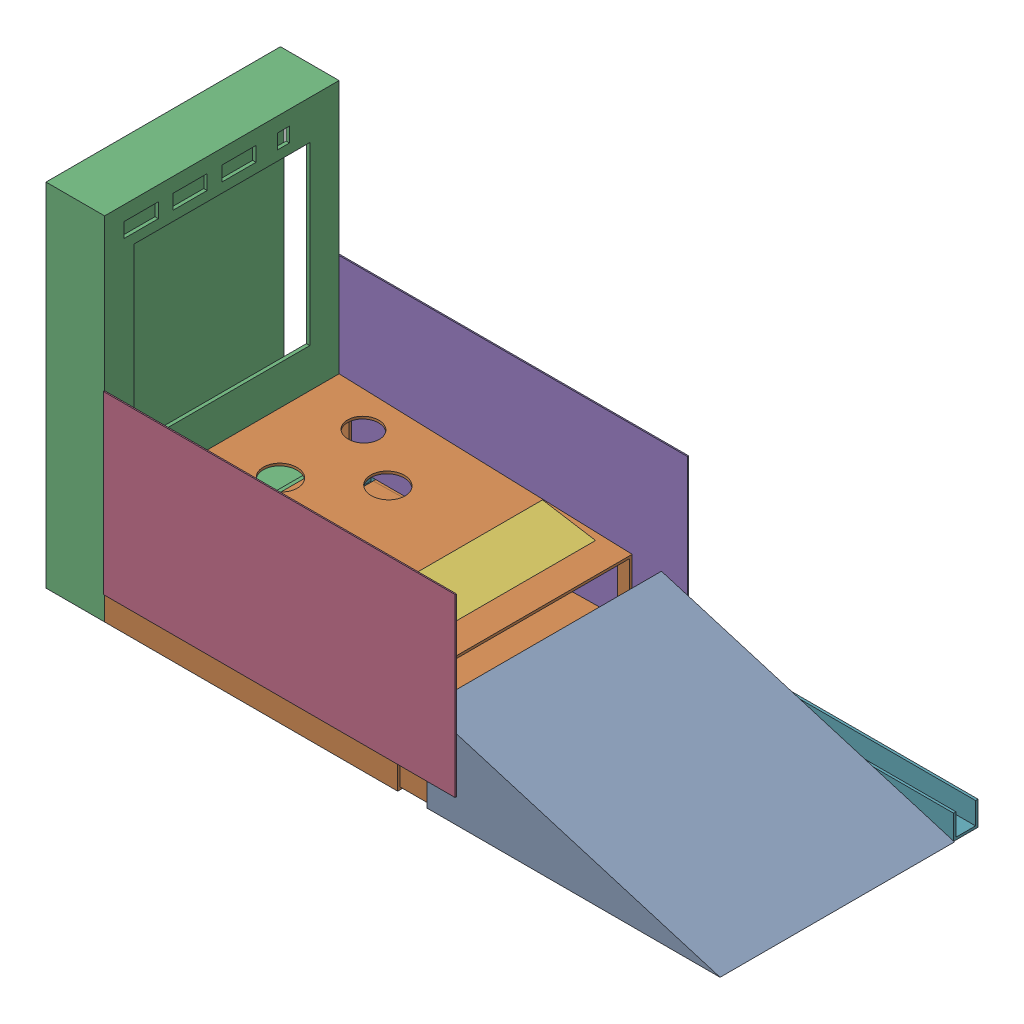
SolidWorks assembly Putting_green_Assem_1, configuration Default. Lengths in mm.
Overall size (1752.6 914.4 676.27).
7 component instances, 6 part files, 17 mates.
Components (placement in the parent):
- Ramp_1-1: Ramp_1 [Default] at (-331.4722 -99.9614 240.936) size (762 228.6 609.6)
- Holes_and_Ball_return-1: Holes_and_Ball_return [Default] at (-795.6906 -99.9614 240.936) size (838.2 254 609.6)
- Display_Backing-1: Display_Backing [Default] at (-1169.6722 -99.9614 -63.864) size (152.4 914.4 609.6)
- Acrylic_side_p_1-1: Acrylic_side_p_1 [Default] at (-712.4722 -36.4614 244.111) size (914.4 457.2 3.17)
- Acrylic_side_p_1-3: Acrylic_side_p_1 [Default] at (-721.3622 -36.4614 -368.664) size (914.4 457.2 3.17)
- Blocker_1-1: Blocker_1 [Default] at (-483.8299 131.1771 -3.7061) x (0.986915 -0.161239 0) z (0 0 1) size (139.7 6.35 571.5)
- ball return-1: ball return [Default] at (-356.204 -99.9614 -432.164) size (1568.45 63.5 63.5)
Mates (geometry in assembly coordinates):
- Coincident1: coincident anti-aligned: plane of Ramp_1-1 through (-331.4722 -93.6114 -368.664) normal (0 1 0); plane of Holes_and_Ball_return-1 through (-1074.4222 -93.6114 980.8589) normal (0 -1 0)
- Coincident2: coincident anti-aligned: plane of Ramp_1-1 through (-331.4722 -99.9614 234.586) normal (0 0 -1); plane of Holes_and_Ball_return-1 through (-795.6906 -99.9614 234.586) normal (0 0 1)
- Coincident3: coincident anti-aligned: plane of Ramp_1-1 through (-331.4722 128.6386 -368.664) normal (-1 0 0); plane of Holes_and_Ball_return-1 through (-331.4722 -93.6114 980.8589) normal (1 0 0)
- Parallel1: parallel aligned: plane of Holes_and_Ball_return-1 through (-795.6906 -99.9614 240.936) normal (0 0 1); plane of Display_Backing-1 through (-1322.0722 -99.9614 240.936) normal (0 0 1)
- Coincident4: coincident aligned: plane of Holes_and_Ball_return-1 through (-795.6906 -99.9614 240.936) normal (0 0 1); plane of Display_Backing-1 through (-1322.0722 -99.9614 240.936) normal (0 0 1)
- Coincident5: coincident aligned: plane of Holes_and_Ball_return-1 through (-1169.6722 -99.9614 -368.664) normal (0 -1 0); plane of Display_Backing-1 through (-1322.0722 -99.9614 240.936) normal (0 -1 0)
- Coincident6: coincident anti-aligned: plane of Holes_and_Ball_return-1 through (-1169.6722 -99.9614 -368.664) normal (-1 0 0); plane of Display_Backing-1 through (-1169.6722 -99.9614 -63.864) normal (1 0 0)
- Coincident7: coincident: line of Holes_and_Ball_return-1 through (-1137.9222 -36.4614 240.936) axis (1 0 0); plane of Acrylic_side_p_1-1 through (-1169.6722 -36.4614 240.936) normal (0 -1 0)
- Coincident8: coincident anti-aligned: plane of Holes_and_Ball_return-1 through (-795.6906 -99.9614 240.936) normal (0 0 1); plane of Acrylic_side_p_1-1 through (-712.4722 -36.4614 240.936) normal (0 0 -1)
- Coincident12: coincident: line of Holes_and_Ball_return-1 through (-1074.4222 -36.4614 -368.664) axis (1 0 0); plane of Acrylic_side_p_1-3 through (-1178.5622 -36.4614 -371.839) normal (0 -1 0)
- Parallel2: parallel aligned: plane of Ramp_1-1 through (-331.4722 -99.9614 -368.664) normal (0 0 -1); plane of Acrylic_side_p_1-3 through (-721.3622 -36.4614 -371.839) normal (0 0 -1)
- Coincident13: coincident anti-aligned: line of Display_Backing-1 through (-1178.5622 -91.0714 -368.664) axis (0 1 0); line of Acrylic_side_p_1-3 through (-1178.5622 420.7386 -368.664) axis (0 -1 0)
- Coincident14: coincident aligned: line of Display_Backing-1 through (-1169.6722 814.4386 240.936) axis (0 -1 0); line of Acrylic_side_p_1-1 through (-1169.6722 420.7386 240.936) axis (0 -1 0)
- Coincident15: coincident aligned: line of Holes_and_Ball_return-1 through (-483.8299 131.1771 221.886) axis (0 0 -1); line of Blocker_1-1 through (-483.8299 131.1771 221.886) axis (0 0 -1)
- Coincident16: coincident anti-aligned: plane of Holes_and_Ball_return-1 through (-503.6414 -463.1695 -349.614) normal (0 0 1); plane of Blocker_1-1 through (-484.8538 124.9102 -349.614) normal (0 0 -1)
- Coincident17: coincident anti-aligned: line of Holes_and_Ball_return-1 through (-1074.4222 -80.9114 -368.664) axis (-1 0 0); line of ball return-1 through (-1134.079 -80.9114 -368.664) axis (1 0 0)
- Parallel3: parallel aligned: plane of Holes_and_Ball_return-1 through (-795.6906 -99.9614 -368.664) normal (0 0 -1); plane of ball return-1 through (-356.204 -99.9614 -375.014) normal (0 0 -1)
